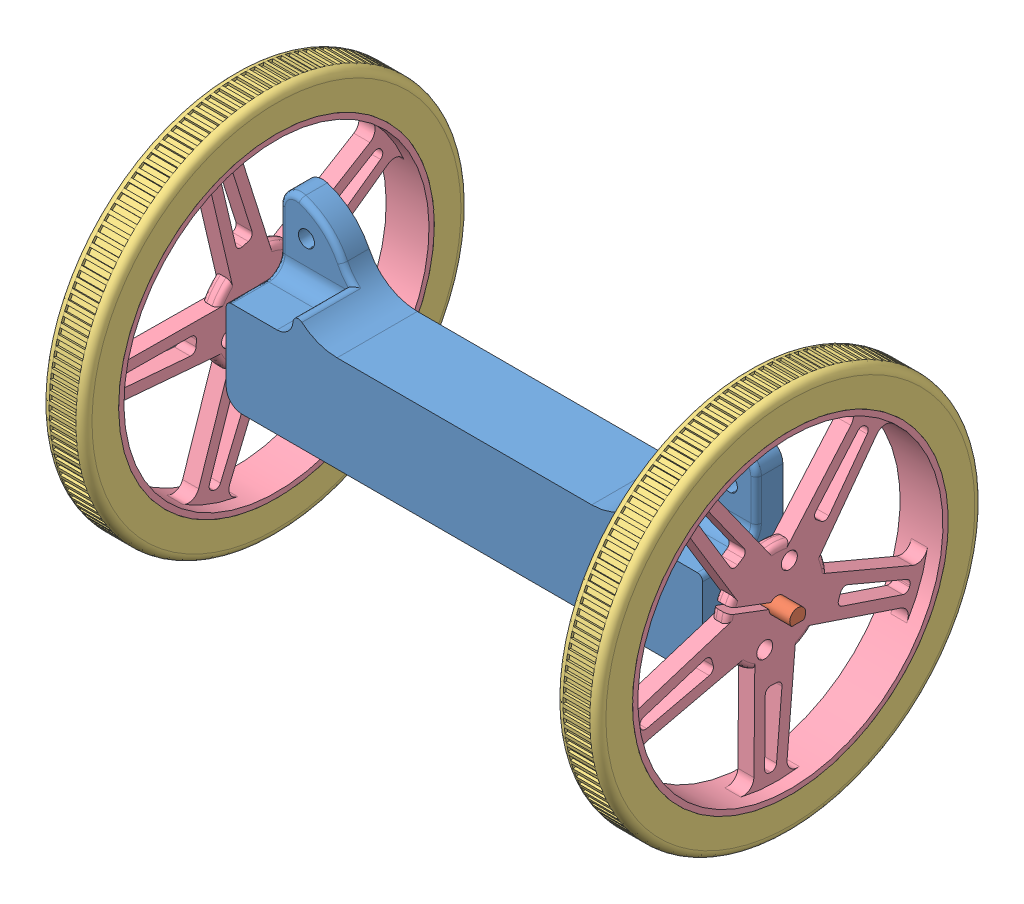
SolidWorks assembly Montagem2, configuration Valor predeterminado. Lengths in mm.
Overall size (105.37 92.69 92.69).
10 component instances, 4 part files, 4 mates.
Components (placement in the parent):
- Motores-Com-Suporte-1: Motores-Com-Suporte [Valor predeterminado] at (-0.0038 -0.3872 15.74) size (104.74 30.54 15)
  - Suporte-Motor-1: Suporte-Motor [Valor predeterminado] at (-3.5493 -86.0959 81.5) size (89 30.54 15)
  - Pololu #2218 Micro Metal Gearmotor HP-1: Pololu #2218 Micro Metal Gearmotor HP [Valor predeterminado] at (-45.1132 -1.497 86.6) x (0 0 1) z (1 0 0) size (10 12 35.52)
  - Pololu #2218 Micro Metal Gearmotor HP-2: Pololu #2218 Micro Metal Gearmotor HP [Valor predeterminado] at (21.8868 -1.497 86.6) x (0 0 -1) z (-1 0 0) size (10 12 35.52)
- Pneu-1: Pneu [Valor predeterminado] at (-56.617 -1.8842 102.34) x (0 -0.264956 0.96426) z (-1 0 0) size (71.92 71.92 8.56)
  - Borracha-1: Borracha [Valor predeterminado] at origin size (71.92 71.92 8)
  - Roda-1: Roda [Valor predeterminado] at origin size (65 65 8.56)
- Pneu-2: Pneu [Valor predeterminado] at (31.383 -1.8842 102.34) x (0 -0.93546 0.353431) z (1 0 0) size (71.92 71.92 8.56)
  - Borracha-1: Borracha [Valor predeterminado] at origin size (71.92 71.92 8)
  - Roda-1: Roda [Valor predeterminado] at origin size (65 65 8.56)
Mates (geometry in assembly coordinates):
- Concêntrico1: concentric: cylinder of Motores-Com-Suporte-1/Pololu #2218 Micro Metal Gearmotor HP-1 through (-54.717 -1.8842 102.34) axis (-1 0 0) radius 1.5; cylinder of Pneu-1/Roda-1 through (-56.117 -1.8842 102.34) axis (-1 0 0) radius 1.5
- Tangente1: tangent: plane of Motores-Com-Suporte-1/Suporte-Motor-1 through (-56.117 -8.0842 112.24) normal (-1 0 0); torus of Pneu-1/Roda-1
- Concêntrico2: concentric: cylinder of Motores-Com-Suporte-1/Pololu #2218 Micro Metal Gearmotor HP-2 through (31.483 -1.8842 102.34) axis (1 0 0) radius 1.5; cylinder of Pneu-2/Roda-1 through (79.6938 -1.8842 102.34) axis (1 0 0) radius 1.5
- Tangente2: tangent: plane of Motores-Com-Suporte-1/Suporte-Motor-1 through (32.883 16.4552 112.24) normal (1 0 0); torus of Pneu-2/Roda-1
